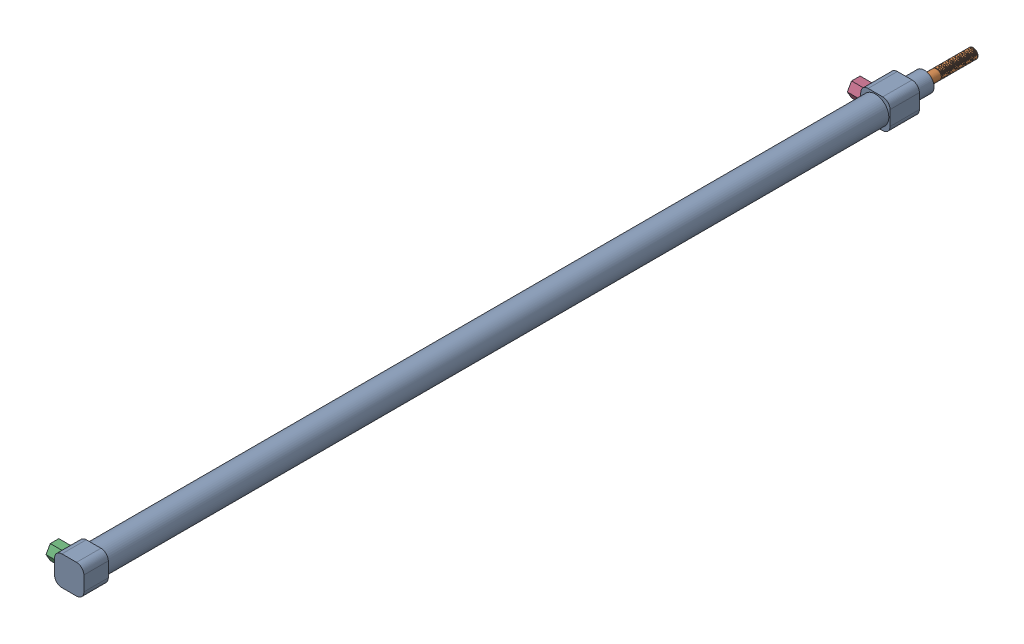
SolidWorks assembly 2210-300气缸装配体, configuration Default. Lengths in mm.
Overall size (18.68 13.36 370.02).
4 component instances, 3 part files, 7 mates.
Components (placement in the parent):
- 22气缸10-300-1: 22气缸10-300 [默认] at (121.2568 174.2105 124.3424) size (12 12 350)
- 22气缸杆10-300-1: 22气缸杆10-300 [默认] at (121.2568 174.2105 444.3424) x (0.899953 0.435988 0) z (0 0 -1) size (10 10 360.02)
- 22气缸嘴10-300-1: 22气缸嘴10-300 [默认] at (118.2568 174.2105 448.3424) x (0 0 1) z (-1 0 0) size (7 6.07 9)
- 22气缸嘴10-300-2: 22气缸嘴10-300 [默认] at (118.2568 174.2105 120.3424) x (0 0 1) z (-1 0 0) size (7 6.07 9)
Mates (geometry in assembly coordinates):
- 同心1: concentric: cylinder of assembly; cylinder of assembly; cylinder of 22气缸10-300-1 through (118.2568 174.2105 448.3424) axis (-1 0 0) radius 2; cylinder of 22气缸嘴10-300-1 through (115.2568 174.2105 448.3424) axis (1 0 0) radius 2
- 重合1: coincident: plane of assembly; plane of assembly; plane of 22气缸10-300-1 through (118.2568 174.2105 448.3424) normal (-1 0 0); plane of 22气缸嘴10-300-1 through (118.2568 174.2105 448.3424) normal (1 0 0)
- 同心2: concentric: cylinder of assembly; cylinder of assembly; cylinder of 22气缸10-300-1 through (118.2568 174.2105 120.3424) axis (-1 0 0) radius 2; cylinder of 22气缸嘴10-300-2 through (115.2568 174.2105 120.3424) axis (1 0 0) radius 2
- 重合2: coincident: plane of assembly; plane of assembly; plane of 22气缸10-300-1 through (118.2568 174.2105 120.3424) normal (-1 0 0); plane of 22气缸嘴10-300-2 through (118.2568 174.2105 120.3424) normal (1 0 0)
- 同心3: concentric: cylinder of assembly; cylinder of assembly; cylinder of 22气缸10-300-1 through (121.2568 174.2105 142.3424) axis (0 0 -1) radius 2; cylinder of 22气缸杆10-300-1 through (121.2568 174.2105 84.3424) axis (0 0 1) radius 2
- 平行1: parallel: plane of assembly; plane of assembly; plane of 22气缸10-300-1 through (118.2568 177.2105 444.3424) normal (0 0 -1); plane of 22气缸杆10-300-1 through (121.2568 174.2105 434.3424) normal (0 0 -1)
- LimitDistance1: limit distance = 0 mm: plane of assembly; plane of assembly; plane of 22气缸杆10-300-1 through (121.2568 174.2105 444.3424) normal (0 0 1); plane of 22气缸10-300-1 through (118.2568 177.2105 444.3424) normal (0 0 -1)
